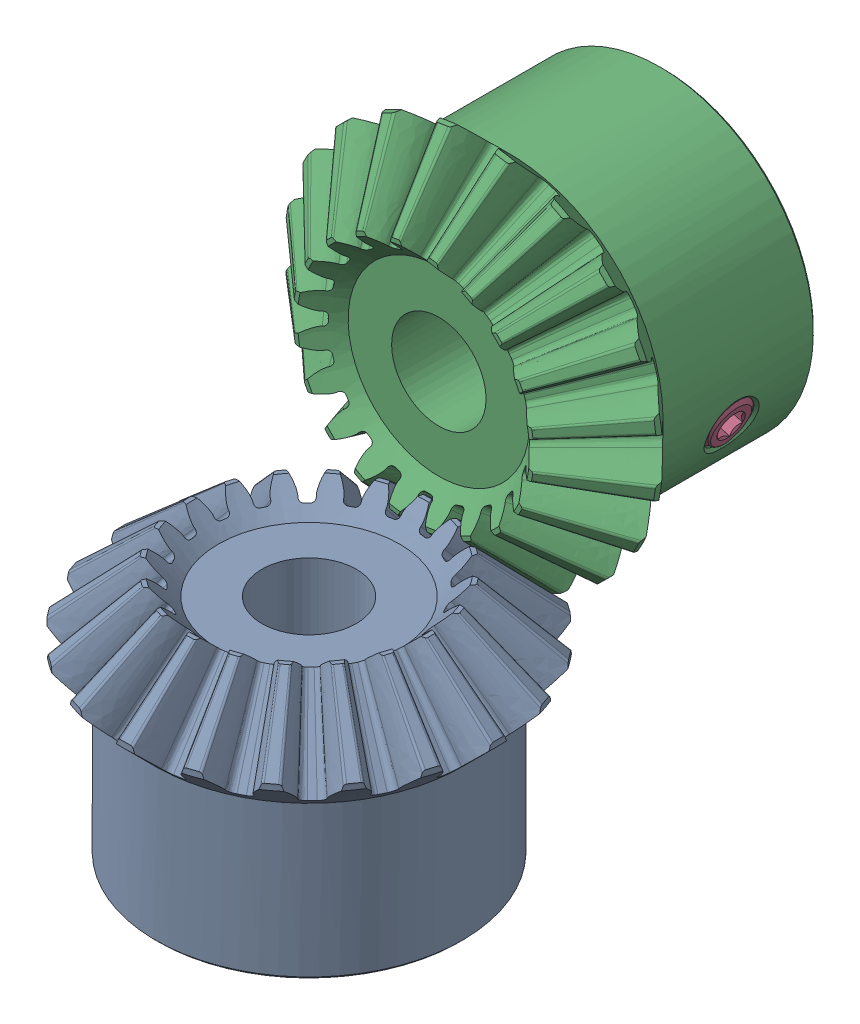
SolidWorks assembly Gear Assembly, configuration Default. Lengths in mm.
Overall size (42.87 50.06 51.44).
2 component instances, 1 part files, 6 mates.
Components (placement in the parent):
- 2600N3_Metal Miter Gear-1: 2600N3_Metal Miter Gear [2600N3] at (0 -15 30) x (0.466229 0 0.884664) z (-0.884664 0 0.466229) size (31.74 21.31 31.74)
- 2600N3_Metal Miter Gear-2: 2600N3_Metal Miter Gear [2600N3] at (0 0 15) x (-0.948972 0.31536 0) z (0.31536 0.948972 0) size (31.74 21.31 31.74)
Mates (geometry in assembly coordinates):
- Concentric4: concentric aligned: cylinder of 2600N3_Metal Miter Gear-2 through (0 0 33.8492) axis (0 0 -1) radius 4
- Distance5: distance = 30 mm: plane of 2600N3_Metal Miter Gear-1 through (0 -30 30) normal (0 -1 0)
- Parallel2: parallel anti-aligned: plane of 2600N3_Metal Miter Gear-1 through (0 -30 30) normal (0 -1 0)
- Coincident13: coincident anti-aligned: plane of 2600N3_Metal Miter Gear-2 through (0 0 0) normal (0 0 -1)
- Concentric8: concentric anti-aligned: cylinder of 2600N3_Metal Miter Gear-1 through (0 1.5 30) axis (0 -1 0) radius 13
- GearMate5: gear = 26 : 26 mm: cylinder of 2600N3_Metal Miter Gear-1 through (0 1.5 30) axis (0 -1 0) radius 13; cylinder of 2600N3_Metal Miter Gear-2 through (0 0 31.5) axis (0 0 -1) radius 13
